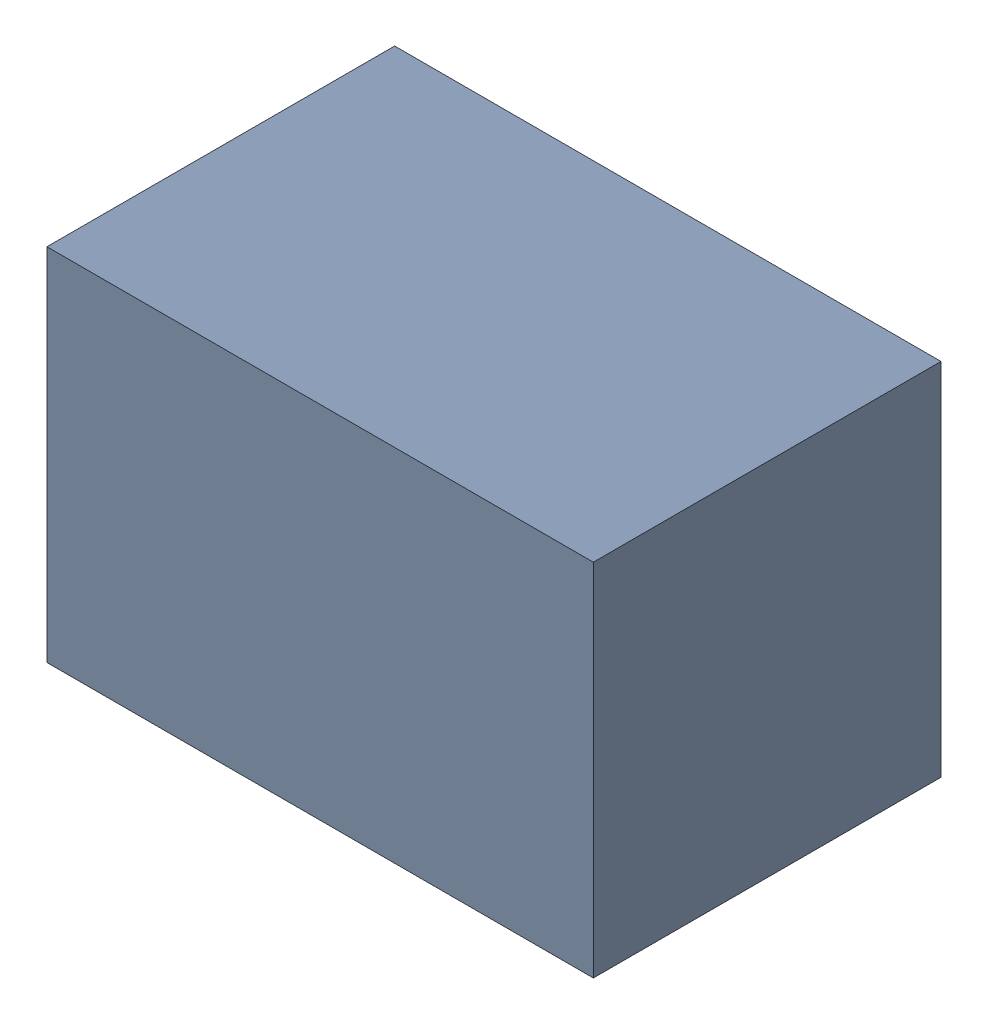
SolidWorks assembly C24, configuration Default. Lengths in mm.
Overall size (2.2 1.45 1.4).
2 component instances, 1 part files, 0 mates.
Components (placement in the parent):
- 1017092848-1: 1017092848 [Default] at (142.24 144.78 0) size (2.2 1.45 1.4)
  - Extruded_3-1: Extruded_3 [Default] at origin size (2.2 1.45 1.4)
